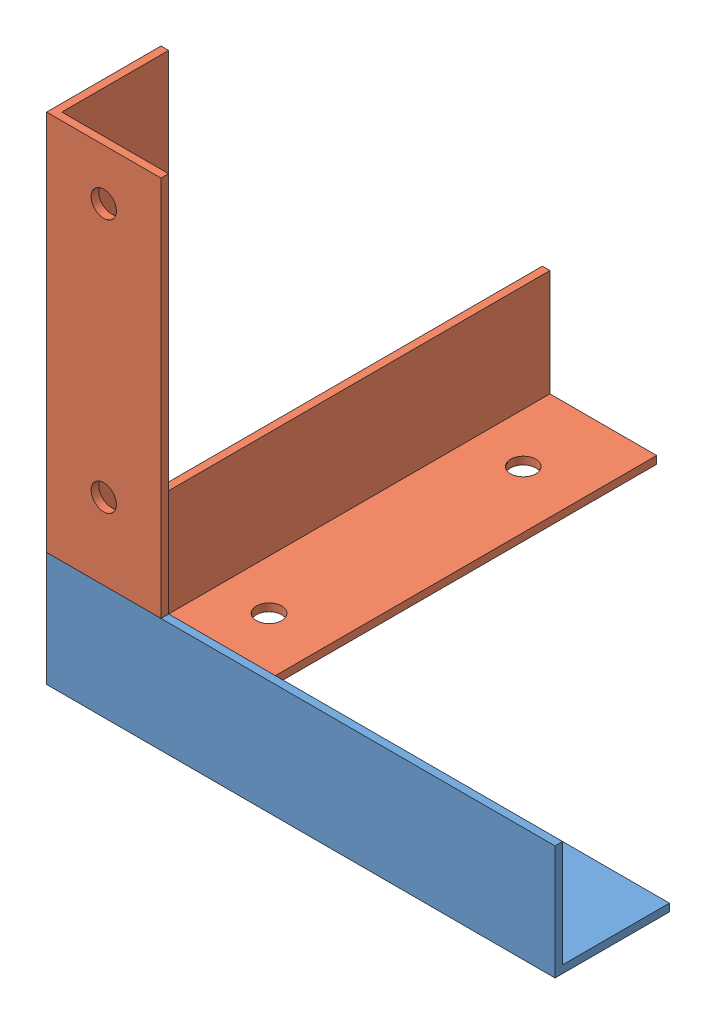
SolidWorks assembly УгольникЛ, configuration По умолчанию. Lengths in mm.
Overall size (130 195 195).
3 component instances, 2 part files, 7 mates.
Components (placement in the parent):
- ШипВ1-1: ШипВ1 [По умолчанию] at origin size (130 45 45)
- ШипГ1-1: ШипГ1 [По умолчанию] at (0 0 -195) x (0 0 1) z (-1 0 0) size (150 45 45)
- ШипГ1-2: ШипГ1 [По умолчанию] at (0 45 0) x (0 1 0) z (-1 0 0) size (150 45 45)
Mates (geometry in assembly coordinates):
- Параллельность1: parallel anti-aligned: plane of ШипВ1-1 through (130 0 0) normal (0 0 1); plane of ШипГ1-1 through (0 0 -195) normal (0 0 -1)
- Совпадение3: coincident aligned: plane of ШипВ1-1 through (130 0 0) normal (0 -1 0); plane of ШипГ1-1 through (0 0 -45) normal (0 -1 0)
- Совпадение6: coincident anti-aligned: plane of ШипВ1-1 through (130 3 -45) normal (0 0 -1); plane of ШипГ1-1 through (0 0 -45) normal (0 0 1)
- Совпадение7: coincident anti-aligned: plane of ШипВ1-1 through (130 45 0) normal (0 1 0); plane of ШипГ1-2 through (0 45 0) normal (0 -1 0)
- Совпадение8: coincident aligned: plane of ШипГ1-1 through (0 0 -45) normal (-1 0 0); plane of ШипГ1-2 through (0 195 0) normal (-1 0 0)
- Совпадение9: coincident aligned: plane of ШипВ1-1 through (130 0 0) normal (0 0 1); plane of ШипГ1-2 through (0 195 0) normal (0 0 1)
- Расстояние1: distance = 0 mm aligned: plane of ШипГ1-1 through (0 0 -45) normal (-1 0 0); plane of ШипВ1-1 through (0 0 0) normal (-1 0 0)
